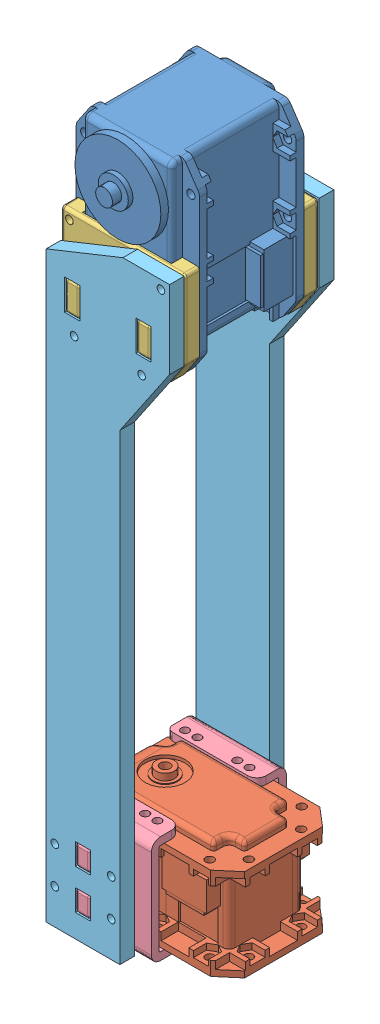
SolidWorks assembly elbow_pitch_link, configuration Default. Lengths in mm.
Overall size (201.45 310.52 126.8).
8 component instances, 5 part files, 22 mates.
Components (placement in the parent):
- RX-64-1: RX-64 [Default] at origin size (40.2 62.1 50)
- RX-28-1: RX-28 [Default] at (-8.1 -197.7 0) x (0 0 1) z (0 -1 0) size (117.84 201.45 118.07)
- Custom Frame - RX 64 to Delrin Plates Lower-1: Custom Frame - RX 64 to Delrin Plates Lower [Default] at (0 -31.65 17) x (0 1 0) z (1 0 0) size (32.9 9.76 40.2)
- Custom Frame - RX 28 to Delrin Plates Upper-1: Custom Frame - RX 28 to Delrin Plates Upper [Default] at (-8.1 -197.7 21) x (-1 0 0) z (0 -1 0) size (29.5 14.36 35)
- Custom Frame - RX 28 to Delrin Plates Upper-2: Custom Frame - RX 28 to Delrin Plates Upper [Default] at (-8.1 -197.7 -21) x (-1 0 0) z (0 1 0) size (29.5 14.36 35)
- Custom Frame - RX 64 to Delrin Plates Lower-2: Custom Frame - RX 64 to Delrin Plates Lower [Default] at (0 -31.65 -17) x (0 1 0) z (-1 0 0) size (32.9 9.76 40.2)
- Connection Plate - RX-64 to RX-28-1: Connection Plate - RX-64 to RX-28 [Default] at (-20.1 -215.2 -22) x (0 1 0) z (0 0 -1) size (200 40.2 4.76)
- Connection Plate - RX-64 to RX-28-2: Connection Plate - RX-64 to RX-28 [Default] at (-20.1 -215.2 26.7625) x (0 1 0) z (0 0 -1) size (200 40.2 4.76)
Mates (geometry in assembly coordinates):
- Coincident94: coincident anti-aligned: plane of RX-64-1 through (-13.52 -42.04 20.5) normal (0 0 1); plane of Custom Frame - RX 64 to Delrin Plates Lower-1 through (14.5 -77.3104 20.5) normal (0 0 -1)
- Concentric56: concentric anti-aligned: cylinder of RX-64-1 through (-17.3 -18 17) axis (0 0 -1) radius 1.35; cylinder of Custom Frame - RX 64 to Delrin Plates Lower-1 through (-17.3 -18 17) axis (0 0 1) radius 1.25
- Concentric57: concentric anti-aligned: cylinder of RX-64-1 through (11 -45.3 17) axis (0 0 -1) radius 1.35; cylinder of Custom Frame - RX 64 to Delrin Plates Lower-1 through (11 -45.3 17) axis (0 0 1) radius 1.25
- Coincident102: coincident anti-aligned: plane of RX-64-1 through (-13.52 -42.01 -20.5) normal (0 0 -1); plane of Custom Frame - RX 64 to Delrin Plates Lower-2 through (-14.5 -77.3104 -20.5) normal (0 0 1)
- Concentric66: concentric aligned: cylinder of RX-64-1 through (11 -45.3 -14.5) axis (0 0 -1) radius 1.35; cylinder of Custom Frame - RX 64 to Delrin Plates Lower-2 through (11 -45.3 -17) axis (0 0 -1) radius 1.25
- Concentric67: concentric aligned: cylinder of RX-64-1 through (17.3 -18 -14.5) axis (0 0 -1) radius 1.35; cylinder of Custom Frame - RX 64 to Delrin Plates Lower-2 through (17.3 -18 -17) axis (0 0 -1) radius 1.25
- Coincident95: coincident anti-aligned: plane of RX-28-1 through (-20.1 -182.7 7.15) normal (0 1 0); plane of Custom Frame - RX 28 to Delrin Plates Upper-1 through (7.95 -182.7 19.132) normal (0 -1 0)
- Concentric58: concentric anti-aligned: cylinder of RX-28-1 through (4.4 -185.2 15) axis (0 -1 0) radius 1.35; cylinder of Custom Frame - RX 28 to Delrin Plates Upper-1 through (4.4 -181.2 15) axis (0 1 0) radius 1.3
- Concentric59: concentric anti-aligned: cylinder of RX-28-1 through (-12.6 -185.2 15) axis (0 -1 0) radius 1.35; cylinder of Custom Frame - RX 28 to Delrin Plates Upper-1 through (-12.6 -181.2 15) axis (0 1 0) radius 1.3
- Coincident98: coincident anti-aligned: plane of RX-28-1 through (-20.1 -182.7 7.15) normal (0 1 0); plane of Custom Frame - RX 28 to Delrin Plates Upper-2 through (7.95 -182.7 -12.268) normal (0 -1 0)
- Concentric64: concentric anti-aligned: cylinder of RX-28-1 through (4.4 -185.2 -15) axis (0 -1 0) radius 1.35; cylinder of Custom Frame - RX 28 to Delrin Plates Upper-2 through (4.4 -181.2 -15) axis (0 1 0) radius 1.3
- Concentric65: concentric anti-aligned: cylinder of RX-28-1 through (-12.6 -185.2 -15) axis (0 -1 0) radius 1.35; cylinder of Custom Frame - RX 28 to Delrin Plates Upper-2 through (-12.6 -181.2 -15) axis (0 1 0) radius 1.3
- Coincident96: coincident aligned: plane of Custom Frame - RX 64 to Delrin Plates Lower-1 through (-20.1 -15.2 22) normal (0 0 1); plane of Custom Frame - RX 28 to Delrin Plates Upper-1 through (4.4072 -212.78 22) normal (0 0 1)
- Parallel19: parallel aligned: plane of Custom Frame - RX 64 to Delrin Plates Lower-1 through (-20.1 -48.1 22) normal (-1 0 0); plane of Custom Frame - RX 28 to Delrin Plates Upper-1 through (-20.1 -182.7636 19.092) normal (-1 0 0)
- Coincident101: coincident aligned: plane of Custom Frame - RX 64 to Delrin Plates Lower-1 through (-20.1 -48.1 22) normal (-1 0 0); plane of Custom Frame - RX 28 to Delrin Plates Upper-1 through (-20.1 -182.7636 19.092) normal (-1 0 0)
- Coincident114: coincident anti-aligned: plane of Custom Frame - RX 28 to Delrin Plates Upper-1 through (4.4072 -212.78 22) normal (0 0 1); plane of Connection Plate - RX-64 to RX-28-2 through (-20.1 -215.2 22) normal (0 0 -1)
- Coincident115: coincident aligned: plane of Custom Frame - RX 28 to Delrin Plates Upper-1 through (7.95 -215.2 12.268) normal (0 -1 0); plane of Connection Plate - RX-64 to RX-28-2 through (3.9 -215.2 22) normal (0 -1 0)
- Coincident116: coincident aligned: plane of Custom Frame - RX 28 to Delrin Plates Upper-1 through (-20.1 -182.7636 19.092) normal (-1 0 0); plane of Connection Plate - RX-64 to RX-28-2 through (-20.1 -25.2 22) normal (-1 0 0)
- Coincident113: coincident aligned: plane of Custom Frame - RX 28 to Delrin Plates Upper-2 through (7.95 -215.2 -19.132) normal (0 -1 0); plane of Connection Plate - RX-64 to RX-28-1 through (3.9 -215.2 -26.7625) normal (0 -1 0)
- Coincident110: coincident anti-aligned: plane of Custom Frame - RX 64 to Delrin Plates Lower-2 through (20.1 -15.2 -22) normal (0 0 -1); plane of Connection Plate - RX-64 to RX-28-1 through (-20.1 -215.2 -22) normal (0 0 1)
- Coincident111: coincident anti-aligned: plane of Custom Frame - RX 64 to Delrin Plates Lower-2 through (14.1 -40.1 -26.7625) normal (0 -1 0); plane of Connection Plate - RX-64 to RX-28-1 through (9.1 -40.1 -22) normal (0 1 0)
- Coincident112: coincident anti-aligned: plane of Custom Frame - RX 64 to Delrin Plates Lower-2 through (14.1 -40.1 -26.7625) normal (1 0 0); plane of Connection Plate - RX-64 to RX-28-1 through (14.1 -40.1 -22) normal (-1 0 0)
